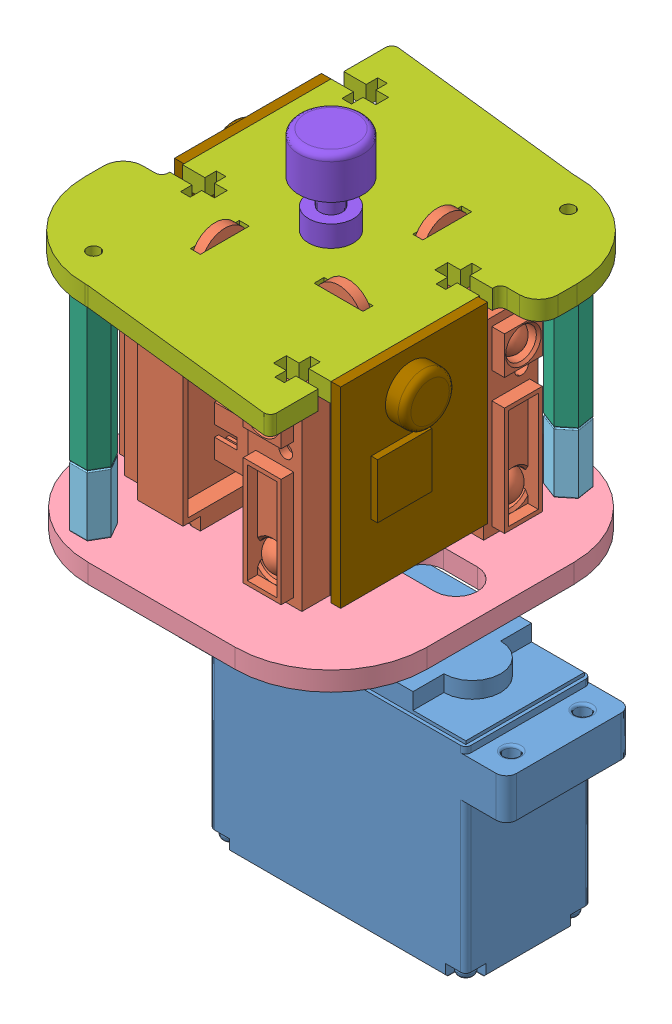
SolidWorks assembly Sensores, configuration Valor predeterminado. Lengths in mm.
Overall size (63.71 96.45 60).
15 component instances, 9 part files, 28 mates.
Components (placement in the parent):
- Servo-HS-311-1: Servo-HS-311 [Default] at (-16.8266 -17.817 9.779) size (52.83 41.27 19.56)
- Sharp_ir_sensor-1: Sharp_ir_sensor [Default] at (-0.6056 58.92 -3.1195) x (0 -1 0) z (1 0 0) size (44.7 18.85 13.49)
- Servo_horn-1: Servo_horn [Valor predeterminado] at (-7.5556 20.029 0) x (-1 0 0) z (0 0 -1) size (10 6.5 10)
- Base_sensores_1-2: Base_sensores_1 [Valor predeterminado] at (-7.5556 24.329 0) size (53 3 53)
- Sharp_ir_sensor-3: Sharp_ir_sensor [Default] at (-10.6751 58.92 -6.95) x (0 -1 0) z (0 0 -1) size (44.7 18.85 13.49)
- Sharp_ir_sensor-4: Sharp_ir_sensor [Default] at (-14.5056 58.92 3.1195) x (0 -1 0) z (-1 0 0) size (44.7 18.85 13.49)
- Sharp_ir_sensor-5: Sharp_ir_sensor [Default] at (-4.4361 58.92 6.95) x (0 -1 0) z (0 0 1) size (44.7 18.85 13.49)
- PC-Standoff - 9.5mm - FF-1: PC-Standoff - 9.5mm - FF [Valor predeterminado] at (-23.2982 27.329 21.3995) x (-1 0 -0.000559) z (0.000559 0 -1) size (5.5 9.5 4.76)
- PC-Standoff - 25mm-1: PC-Standoff - 25mm [Valor predeterminado] at (-23.2982 36.829 21.3995) size (5.5 29.76 4.76)
- PC-Standoff - 9.5mm - FF-2: PC-Standoff - 9.5mm - FF [Valor predeterminado] at (8.1871 27.329 -21.3995) x (0.159853 0 0.987141) z (-0.987141 0 0.159853) size (5.5 9.5 4.76)
- PC-Standoff - 25mm-2: PC-Standoff - 25mm [Valor predeterminado] at (8.1871 36.829 -21.3995) x (0.93482 0 0.355121) z (-0.355121 0 0.93482) size (5.5 29.76 4.76)
- Base_sensores_2-2: Base_sensores_2 [Valor predeterminado] at (-7.5556 61.829 0) x (-1 0 0) z (0 0 -1) size (53 3 60)
- Push_button_1-1: Push_button_1 [Valor predeterminado] at (-7.5556 55.829 0) x (0.957507 0 0.288409) z (-0.288409 0 0.957507) size (10 36.8 10)
- sensor_temperatura-1: sensor_temperatura [Valor predeterminado] at (-28.0556 34.829 2.5) x (0 1 0) z (0 0 1) size (30 4.5 23)
- sensor_temperatura-2: sensor_temperatura [Valor predeterminado] at (12.9444 34.829 -2.5) x (0 1 0) z (0 0 -1) size (30 4.5 23)
Mates (geometry in assembly coordinates):
- Concêntrico1: concentric anti-aligned: cylinder of Servo-HS-311-1 through (-7.5556 23.458 0) axis (0 -1 0) radius 2.794; cylinder of Servo_horn-1 through (-7.5556 20.029 0) axis (0 1 0) radius 2.8
- Coincidente1: coincident anti-aligned: plane of Servo-HS-311-1 through (-7.5556 20.029 0) normal (0 1 0); plane of Servo_horn-1 through (-7.5556 20.029 0) normal (0 -1 0)
- Coincidente6: coincident anti-aligned: plane of Servo_horn-1 through (-3.7556 24.329 -5) normal (0 1 0); plane of Base_sensores_1-2 through (18.9444 24.329 -26.5) normal (0 -1 0)
- Coincidente8: coincident anti-aligned: plane of Sharp_ir_sensor-1 through (-0.6056 58.92 -16.2005) normal (-1 0 0); plane of Base_sensores_1-2 through (-0.6056 17.329 -13.5) normal (1 0 0)
- Coincidente9: coincident anti-aligned: plane of Sharp_ir_sensor-1 through (0.9184 80.4956 -5.85) normal (0 0 1); plane of Base_sensores_1-2 through (-0.6056 17.329 -5.85) normal (0 0 -1)
- Distância1: distance = 2 mm anti-aligned: plane of Sharp_ir_sensor-1 through (6.5064 29.329 -3.1195) normal (0 -1 0); plane of Base_sensores_1-2 through (18.9444 27.329 -26.5) normal (0 1 0)
- Coincidente12: coincident anti-aligned: plane of Base_sensores_1-2 through (18.9444 27.329 -26.5) normal (0 1 0); plane of PC-Standoff - 9.5mm - FF-1 through (-26.0464 27.329 21.398) normal (0 -1 0)
- Concêntrico3: concentric aligned: cylinder of Base_sensores_1-2 through (-23.2982 24.329 21.3995) axis (0 1 0) radius 1; cylinder of PC-Standoff - 9.5mm - FF-1 through (-23.2982 32.069 21.3995) axis (0 1 0) radius 1.0922
- Concêntrico4: concentric aligned: cylinder of PC-Standoff - 9.5mm - FF-1 through (-23.2982 32.069 21.3995) axis (0 1 0) radius 1.0922; cylinder of PC-Standoff - 25mm-1 through (-23.2982 32.069 21.3995) axis (0 1 0) radius 1.0922
- Coincidente13: coincident anti-aligned: plane of PC-Standoff - 9.5mm - FF-1 through (-26.0464 36.829 21.398) normal (0 1 0); plane of PC-Standoff - 25mm-1 through (-20.55 36.829 21.3995) normal (0 -1 0)
- Concêntrico5: concentric aligned: cylinder of PC-Standoff - 9.5mm - FF-2 through (8.1871 32.069 -21.3995) axis (0 1 0) radius 1.0922; cylinder of PC-Standoff - 25mm-2 through (8.1871 32.069 -21.3995) axis (0 1 0) radius 1.0922
- Coincidente14: coincident anti-aligned: plane of PC-Standoff - 9.5mm - FF-2 through (8.6264 36.829 -18.6866) normal (0 1 0); plane of PC-Standoff - 25mm-2 through (10.7561 36.829 -20.4236) normal (0 -1 0)
- Coincidente15: coincident anti-aligned: plane of Base_sensores_1-2 through (18.9444 27.329 -26.5) normal (0 1 0); plane of PC-Standoff - 9.5mm - FF-2 through (8.6264 27.329 -18.6866) normal (0 -1 0)
- Concêntrico6: concentric aligned: cylinder of Base_sensores_1-2 through (8.1871 24.329 -21.3995) axis (0 1 0) radius 1; cylinder of PC-Standoff - 9.5mm - FF-2 through (8.1871 32.069 -21.3995) axis (0 1 0) radius 1.0922
- Concêntrico7: concentric aligned: cylinder of PC-Standoff - 25mm-1 through (-23.2982 57.069 21.3995) axis (0 1 0) radius 1.0922; cylinder of Base_sensores_2-2 through (-23.2982 61.829 21.3995) axis (0 1 0) radius 1
- Coincidente16: coincident anti-aligned: plane of PC-Standoff - 25mm-1 through (-20.55 61.829 21.3995) normal (0 1 0); plane of Base_sensores_2-2 through (-34.0556 61.829 30) normal (0 -1 0)
- Concêntrico8: concentric aligned: cylinder of PC-Standoff - 25mm-2 through (8.1871 57.069 -21.3995) axis (0 1 0) radius 1.0922; cylinder of Base_sensores_2-2 through (8.1871 61.829 -21.3995) axis (0 1 0) radius 1
- Coincidente17: coincident anti-aligned: plane of Servo_horn-1 through (-11.3556 24.329 5) normal (1 0 0); plane of Base_sensores_1-2 through (-11.3556 24.329 -5) normal (-1 0 0)
- Coincidente18: coincident anti-aligned: plane of Servo_horn-1 through (-2.5556 26.529 5) normal (0 0 1); plane of Base_sensores_1-2 through (-12.5556 24.329 5) normal (0 0 -1)
- Concêntrico9: concentric anti-aligned: cylinder of Base_sensores_2-2 through (-7.5556 61.829 0) axis (0 1 0) radius 3.5; cylinder of Push_button_1-1 through (-7.5556 68.129 0) axis (0 -1 0) radius 3.5
- Coincidente19: coincident anti-aligned: plane of Base_sensores_2-2 through (-34.0556 61.829 30) normal (0 -1 0); plane of Push_button_1-1 through (-7.5556 61.829 0) normal (0 1 0)
- Coincidente20: coincident anti-aligned: plane of Base_sensores_2-2 through (-28.0556 61.829 6) normal (-1 0 0); plane of sensor_temperatura-1 through (-28.0556 34.829 -20.5) normal (1 0 0)
- Paralelo1: parallel anti-aligned: plane of Servo-HS-311-1 through (-16.8266 -17.817 9.779) normal (0 0 1); plane of Servo_horn-1 through (-7.5556 20.029 0) normal (0 0 -1)
- Distância2: distance = 0 mm aligned: plane of sensor_temperatura-1 through (-29.5556 34.829 -20.5) normal (0 0 -1); plane of Base_sensores_2-2 through (-24.5556 61.829 -20.5) normal (0 0 -1)
- Coincidente25: coincident aligned: plane of Base_sensores_2-2 through (-34.0556 64.829 30) normal (0 1 0); plane of sensor_temperatura-1 through (-29.5556 64.829 2.5) normal (0 1 0)
- Coincidente26: coincident anti-aligned: plane of Base_sensores_2-2 through (12.9444 61.829 -6) normal (1 0 0); plane of sensor_temperatura-2 through (12.9444 34.829 20.5) normal (-1 0 0)
- Distância3: distance = 0 mm aligned: plane of sensor_temperatura-2 through (14.4444 34.829 20.5) normal (0 0 1); plane of Base_sensores_2-2 through (9.4444 61.829 20.5) normal (0 0 1)
- Coincidente27: coincident aligned: plane of Base_sensores_2-2 through (-34.0556 64.829 30) normal (0 1 0); plane of sensor_temperatura-2 through (14.4444 64.829 -2.5) normal (0 1 0)
